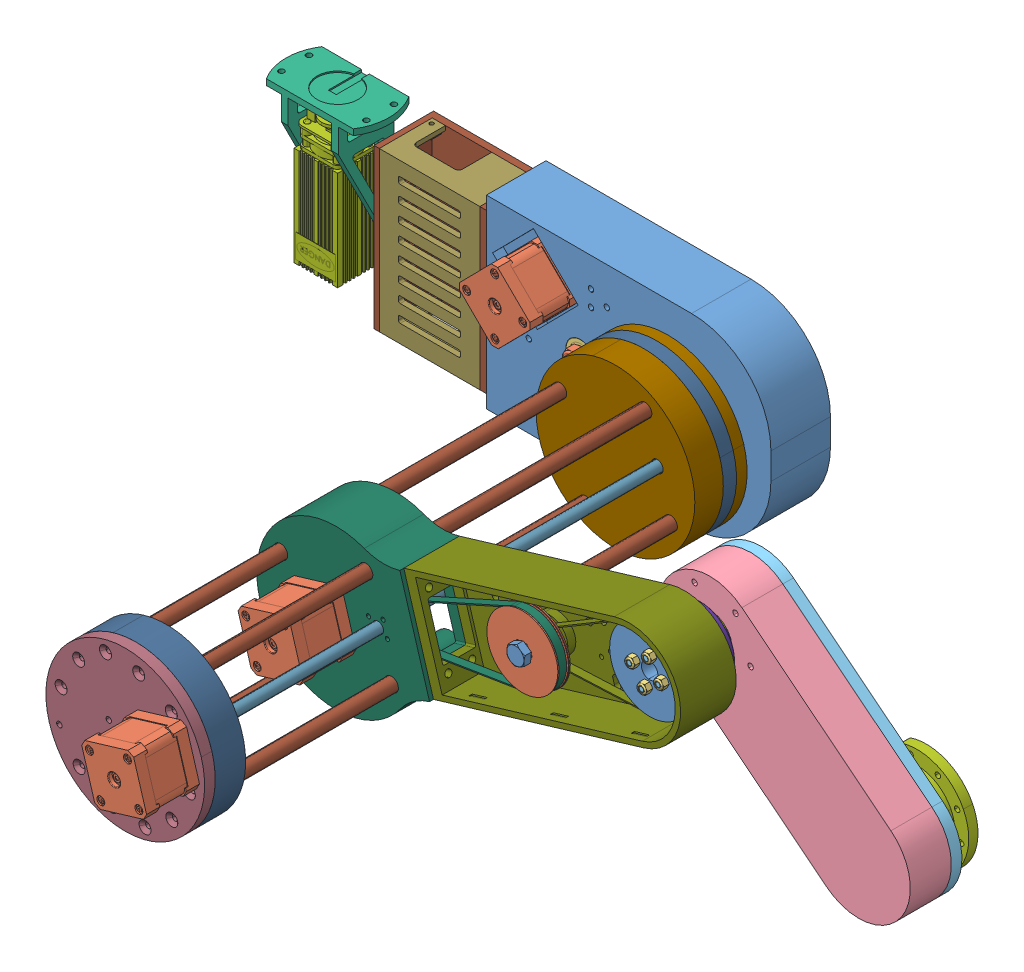
SolidWorks assembly SCARA Robot 3D Model dimensions, configuration Default. Lengths in mm.
Overall size (711.3 199.33 508).
113 component instances, 59 part files, 0 mates.
Components (placement in the parent):
- SCARA Robot 3D Model.STEP-1: SCARA Robot 3D Model.STEP [Default] at origin size (715.3 199.33 508)
  - Gripper Mechanism_Gripper Mechanism.STEP-1: Gripper Mechanism_Gripper Mechanism.STEP [Default] at (330.7722 20.5016 165.2282) x (0.989399 0.145223 0) z (0 0 -1) size (125 64.7 115.06) (hidden)
    - Servo Holder_Servo Holder.STEP-1: Servo Holder_Servo Holder.STEP [Default] at (30.6623 30.9064 53.3617) size (44 15 72.5)
    - Servo Motor MG996R 3D Model_Servo Motor MG996R 3D Model.STEP-1: Servo Motor MG996R 3D Model_Servo Motor MG996R 3D Model.STEP [Default] at (30.6623 -0.2936 62.3617) x (0 0 1) z (-1 0 0) size (55.8 45.2 20.5)
    - Servo MG996R Horn_Servo MG996R Horn.STEP-1: Servo MG996R Horn_Servo MG996R Horn.STEP [Default] at (30.6623 44.9064 52.1117) x (0.468503 0 0.883462) z (-0.883462 0 0.468503) size (32 2.5 12)
    - Gripper Cover_Gripper Cover.STEP-1: Gripper Cover_Gripper Cover.STEP [Default] at (30.6623 56.4064 52.1117) x (-1 0 0) z (0 0 1) size (44 10.5 70)
    - Gripper Hand Left_Gripper Hand Left.STEP-1: Gripper Hand Left_Gripper Hand Left.STEP [Default] at (0.1145 53.9064 27.1117) size (26 4 105)
    - Gripper rail 6mm_Gripper rail 6mm.STEP-1: Gripper rail 6mm_Gripper rail 6mm.STEP [Default] at (-31.8377 44.9064 75.1117) x (0 0.568693 0.82255) z (0 0.82255 -0.568693) size (6 125 6)
    - Gripper End_Gripper End.STEP-1: Gripper End_Gripper End.STEP [Default] at (-23.3855 44.9064 114.1117) x (0 0 1) z (0 1 0) size (27.12 30 25.12)
    - Gripper Hand Right_Gripper Hand Left.STEP-1: Gripper Hand Right_Gripper Hand Left.STEP [Default] at (61.21 53.9064 27.1117) size (26 4 105)
    - Gripper rail 6mm_Gripper rail 6mm.STEP-2: Gripper rail 6mm_Gripper rail 6mm.STEP [Default] at (93.1623 44.9064 29.1117) x (0 0.838695 -0.544602) z (0 0.544602 0.838695) size (6 125 6)
    - Gripper Mechanism Slider_Gripper Mechanism Slider.STEP-1: Gripper Mechanism Slider_Gripper Mechanism Slider.STEP [Default] at (-20.8855 44.9064 52.1117) x (0 1 0) z (0 0 -1) size (18 26 60)
    - Gripper Mechanism Slider_Gripper Mechanism Slider.STEP-2: Gripper Mechanism Slider_Gripper Mechanism Slider.STEP [Default] at (82.21 44.9064 52.1117) x (0 -1 0) z (0 0 -1) size (18 26 60)
    - Gripper Hand Left_Gripper Hand Left.STEP-2: Gripper Hand Left_Gripper Hand Left.STEP [Default] at (0.1145 31.9064 27.1117) size (26 4 105)
    - Gripper Hand Right_Gripper Hand Left.STEP-2: Gripper Hand Right_Gripper Hand Left.STEP [Default] at (61.21 31.9064 27.1117) size (26 4 105)
    - Gripper End_Gripper End.STEP-2: Gripper End_Gripper End.STEP [Default] at (84.71 44.9064 114.1117) x (0 0 -1) z (0 1 0) size (27.12 30 25.12)
    - Gripper link 1_Gripper link 1.STEP-1: Gripper link 1_Gripper link 1.STEP [Default] at (24.3375 47.4064 40.185) x (0.897148 0 -0.441731) z (0.441731 0 0.897148) size (34.2 3.5 7.2)
    - Gripper link 2_Gripper link 2.STEP-1: Gripper link 2_Gripper link 2.STEP [Default] at (0.1145 39.9064 52.1117) x (-0.897148 0 0.441731) z (-0.441731 0 -0.897148) size (34.2 5 7.2)
    - Gripper link 1_Gripper link 1.STEP-2: Gripper link 1_Gripper link 1.STEP [Default] at (61.21 47.4064 52.1117) x (0.897148 0 -0.441731) z (0.441731 0 0.897148) size (34.2 3.5 7.2)
    - Gripper link 2_Gripper link 2.STEP-2: Gripper link 2_Gripper link 2.STEP [Default] at (36.9871 44.9064 64.0385) x (-0.897148 0 0.441731) z (0.441731 0 0.897148) size (34.2 5 7.2)
    - Gripper to J3 connector_Gripper to J3 connector.STEP-1: Gripper to J3 connector_Gripper to J3 connector.STEP [Default] at (30.6623 44.9064 17.1117) x (0 -1 0) z (1 0 0) size (39 4.5 78)
  - Base_Base.STEP-1: Base_Base.STEP [Default] x (1 0 0) z (0 -1 0) size (215 45 140)
  - Stepper NEMA 17 -  20mm shaft_Stepper NEMA 17 -  20mm shaft.STEP-1: Stepper NEMA 17 -  20mm shaft_Stepper NEMA 17 -  20mm shaft.STEP [Default] at (-89.369 -0.1561 63.0261) x (-0.712104 0.702074 0) z (0 0 -1) size (41 41 60)
  - Ball Bearing 608 - 8x22x7mm_Ball Bearing 608 - 8x22x7mm.STEP-1: Ball Bearing 608 - 8x22x7mm_Ball Bearing 608 - 8x22x7mm.STEP [Default] at (-36.5 0 3) x (0.721176 0.692752 0) z (0.692752 -0.721176 0) size (22 7 22)
  - Ball Bearing 608 - 8x22x7mm_Ball Bearing 608 - 8x22x7mm.STEP-2: Ball Bearing 608 - 8x22x7mm_Ball Bearing 608 - 8x22x7mm.STEP [Default] at (-36.5 0 -7.5) x (0.799042 0.601276 0) z (0.601276 -0.799042 0) size (22 7 22)
  - Thrust Bearing - 40x60x13_Thrust Bearing - 40x60x13.STEP-1: Thrust Bearing - 40x60x13_Thrust Bearing - 40x60x13.STEP [Default] at (42.5 0 -13) x (0.837169 0.546944 0) z (0.546944 -0.837169 0) size (60 13 60)
  - Thrust Bearing - 40x60x13_Thrust Bearing - 40x60x13.STEP-2: Thrust Bearing - 40x60x13_Thrust Bearing - 40x60x13.STEP [Default] at (42.5 0 10) x (0.867502 0.497433 0) z (0.497433 -0.867502 0) size (60 13 60)
  - GT2 Pulley - 110 teeth - J1_GT2 Pulley - Parametric.STEP-1: GT2 Pulley - 110 teeth - J1_GT2 Pulley - Parametric.STEP [Default] at (42.5 0 -11.2) x (-0.957748 -0.287609 0) z (0.287609 -0.957748 0) size (71.92 22.4 71.92)
  - GT2 Pulley - 22 - 80 teeth_GT2 Pulley - Parametric.STEP-1: GT2 Pulley - 22 - 80 teeth_GT2 Pulley - Parametric.STEP [Default] at (-36.5 0 -26.7) x (0.869592 0.493772 0) z (0.493772 -0.869592 0) size (52.82 18.8 52.82)
  - GT2 Pulley - Parametric_GT2 Pulley - Parametric.STEP-1: GT2 Pulley - Parametric_GT2 Pulley - Parametric.STEP [Default] at (-69.2568 32.2954 -19.7) x (-1 0 0) z (0 -1 0) size (14.62 15.2 14.62)
  - M8 Washer_M8 Washer.STEP-1: M8 Washer_M8 Washer.STEP [Default] at (-36.5 0 -9.1) x (0.991676 -0.12876 0) z (-0.12876 -0.991676 0) size (14 1.6 14)
  - J1 coupler_J1 coupler.STEP-1: J1 coupler_J1 coupler.STEP [Default] at (42.5 0 23) x (0.287609 -0.957748 0) z (-0.957748 -0.287609 0) size (120 27 120)
  - Z-axis Bottom Plate_Z-axis Bottom Plate.STEP-1: Z-axis Bottom Plate_Z-axis Bottom Plate.STEP [Default] at (42.5 0 31) x (-0.287609 0.957748 0) z (0.957748 0.287609 0) size (120 10 120)
  - Smooth Rod D10mm L400mm_Smooth Rod D10mm L400mm.STEP-1: Smooth Rod D10mm L400mm_Smooth Rod D10mm L400mm.STEP [Default] at (65.0083 41.8285 25) x (-0.981883 -0.189487 0) z (-0.189487 0.981883 0) size (10 400 10)
  - Smooth Rod D10mm L400mm_Smooth Rod D10mm L400mm.STEP-2: Smooth Rod D10mm L400mm_Smooth Rod D10mm L400mm.STEP [Default] at (84.3285 -22.5083 25) x (0.837169 0.546944 0) z (0.546944 -0.837169 0) size (10 400 10)
  - Smooth Rod D10mm L400mm_Smooth Rod D10mm L400mm.STEP-3: Smooth Rod D10mm L400mm_Smooth Rod D10mm L400mm.STEP [Default] at (19.9917 -41.8285 25) x (0.837169 0.546944 0) z (0.546944 -0.837169 0) size (10 400 10)
  - Smooth Rod D10mm L400mm_Smooth Rod D10mm L400mm.STEP-4: Smooth Rod D10mm L400mm_Smooth Rod D10mm L400mm.STEP [Default] at (0.6715 22.5083 25) x (0.837169 0.546944 0) z (0.546944 -0.837169 0) size (10 400 10)
  - Smooth Rod Clamp_Smooth Rod Clamp.STEP-1: Smooth Rod Clamp_Smooth Rod Clamp.STEP [Default] at (84.3285 -22.5083 41) x (0.47386 0.8806 0) z (0.8806 -0.47386 0) size (39.1 14 26.4)
  - Smooth Rod Clamp_Smooth Rod Clamp.STEP-2: Smooth Rod Clamp_Smooth Rod Clamp.STEP [Default] at (19.9917 -41.8285 41) x (0.8806 -0.47386 0) z (-0.47386 -0.8806 0) size (39.1 14 26.4)
  - Smooth Rod Clamp_Smooth Rod Clamp.STEP-3: Smooth Rod Clamp_Smooth Rod Clamp.STEP [Default] at (0.6715 22.5083 41) x (-0.47386 -0.8806 0) z (-0.8806 0.47386 0) size (39.1 14 26.4)
  - Smooth Rod Clamp_Smooth Rod Clamp.STEP-4: Smooth Rod Clamp_Smooth Rod Clamp.STEP [Default] at (65.0083 41.8285 41) x (-0.8806 0.47386 0) z (0.47386 0.8806 0) size (39.1 14 26.4)
  - Z-axis Top Plate_Z-axis Top Plate.STEP-1: Z-axis Top Plate_Z-axis Top Plate.STEP [Default] at (42.5 0 425) x (-0.287609 0.957748 0) z (0.957748 0.287609 0) size (120 26 120)
  - Smooth Rod Clamp_Smooth Rod Clamp.STEP-5: Smooth Rod Clamp_Smooth Rod Clamp.STEP [Default] at (19.9917 -41.8285 411) x (0.8806 -0.47386 0) z (-0.47386 -0.8806 0) size (39.1 14 26.4)
  - Smooth Rod Clamp_Smooth Rod Clamp.STEP-6: Smooth Rod Clamp_Smooth Rod Clamp.STEP [Default] at (84.3285 -22.5083 411) x (0.47386 0.8806 0) z (0.8806 -0.47386 0) size (39.1 14 26.4)
  - Smooth Rod Clamp_Smooth Rod Clamp.STEP-7: Smooth Rod Clamp_Smooth Rod Clamp.STEP [Default] at (65.0083 41.8285 411) x (-0.8806 0.47386 0) z (0.47386 0.8806 0) size (39.1 14 26.4)
  - Smooth Rod Clamp_Smooth Rod Clamp.STEP-8: Smooth Rod Clamp_Smooth Rod Clamp.STEP [Default] at (0.6715 22.5083 411) x (-0.47386 -0.8806 0) z (-0.8806 0.47386 0) size (39.1 14 26.4)
  - Lead Screw D8mm L380mm_Lead Screw D8mm L380mm.STEP-1: Lead Screw D8mm L380mm_Lead Screw D8mm L380mm.STEP [Default] at (74.1057 9.4911 33) x (0.851295 0.524688 0) z (0.524688 -0.851295 0) size (8 380 8)
  - Ball Bearing 608 - 8x22x7mm_Ball Bearing 608 - 8x22x7mm.STEP-3: Ball Bearing 608 - 8x22x7mm_Ball Bearing 608 - 8x22x7mm.STEP [Default] at (74.1057 9.4911 34) x (0.619704 0.784836 0) z (0.784836 -0.619704 0) size (22 7 22)
  - Stepper NEMA 17 -  20mm shaft_Stepper NEMA 17 -  20mm shaft.STEP-2: Stepper NEMA 17 -  20mm shaft_Stepper NEMA 17 -  20mm shaft.STEP [Default] at (40.8832 -9.3202 494.0261) x (-0.287609 0.957748 0) z (0 0 -1) size (41 41 60)
  - Z-axis Mount Platform_Z-axis Mount Platform.STEP-1: Z-axis Mount Platform_Z-axis Mount Platform.STEP [Default] at (42.5 0 273.6165) x (0.287609 -0.957748 0) z (0.957748 0.287609 0) size (120 45 122)
  - Arm 1_Arm 1.STEP-1: Arm 1_Arm 1.STEP [Default] at (260.8665 65.5748 228.6165) x (0.957748 0.287609 0) z (0.287609 -0.957748 0) size (205 42 78)
  - Ball Bearing 608 - 8x22x7mm_Ball Bearing 608 - 8x22x7mm.STEP-4: Ball Bearing 608 - 8x22x7mm_Ball Bearing 608 - 8x22x7mm.STEP [Default] at (174.6692 39.69 244.6165) x (0.951346 -0.308126 0) z (0.308126 0.951346 0) size (22 7 22)
  - Ball Bearing 608 - 8x22x7mm_Ball Bearing 608 - 8x22x7mm.STEP-5: Ball Bearing 608 - 8x22x7mm_Ball Bearing 608 - 8x22x7mm.STEP [Default] at (174.6692 39.69 235.6165) x (0.947952 -0.318412 0) z (0.318412 0.947952 0) size (22 7 22)
  - J2 Coupler_J2 Coupler.STEP-1: J2 Coupler_J2 Coupler.STEP [Default] at (260.8665 65.5748 209.6165) x (0.148527 0.988908 0) z (0.988908 -0.148527 0) size (78 24 80.24) (hidden)
  - Thrust Bearing 35x52x12mm_Thrust Bearing 35x52x12mm.STEP-1: Thrust Bearing 35x52x12mm_Thrust Bearing 35x52x12mm.STEP [Default] at (260.8665 65.5748 216.6165) x (0.837351 0.546665 0) z (0.546665 -0.837351 0) size (52 12 52)
  - Ball Bearing 30x42x7mm_Ball Bearing 30x42x7mm.STEP-1: Ball Bearing 30x42x7mm_Ball Bearing 30x42x7mm.STEP [Default] at (260.8665 65.5748 231.6165) x (0.837351 0.546665 0) z (0.546665 -0.837351 0) size (42 7 42)
  - GT2 Pulley - 92 teeth - J2_GT2 Pulley - Parametric.STEP-1: GT2 Pulley - 92 teeth - J2_GT2 Pulley - Parametric.STEP [Default] at (260.8665 65.5748 246.8165) x (0.988908 -0.148527 0) z (-0.148527 -0.988908 0) size (60.46 20.4 60.46)
  - GT2 Pulley - 23 - 80 teeth_GT2 Pulley - Parametric.STEP-1: GT2 Pulley - 23 - 80 teeth_GT2 Pulley - Parametric.STEP [Default] at (174.6692 39.69 263.8165) x (-0.997581 -0.069512 0) z (0.069512 -0.997581 0) size (53.62 18.8 53.62)
  - Thrust Bearing 35x52x12mm_Thrust Bearing 35x52x12mm.STEP-2: Thrust Bearing 35x52x12mm_Thrust Bearing 35x52x12mm.STEP [Default] at (260.8665 65.5748 238.6165) x (0.837351 0.546665 0) z (0.546665 -0.837351 0) size (52 12 52)
  - Stepper NEMA 17 -  20mm shaft_Stepper NEMA 17 -  20mm shaft.STEP-3: Stepper NEMA 17 -  20mm shaft_Stepper NEMA 17 -  20mm shaft.STEP [Default] at (-0.3 -21.6874 334.6426) x (-0.287609 0.957748 0) z (0 0 -1) size (41 41 60)
  - GT2 Pulley - Parametric_GT2 Pulley - Parametric.STEP-2: GT2 Pulley - Parametric_GT2 Pulley - Parametric.STEP [Default] at (32.9225 -2.8761 263.8165) x (-0.907133 0.420845 0) z (-0.420845 -0.907133 0) size (14.62 15.2 14.62)
  - M8 Washer_M8 Washer.STEP-2: M8 Washer_M8 Washer.STEP [Default] at (174.6692 39.69 244.6165) x (0.991676 -0.12876 0) z (-0.12876 -0.991676 0) size (14 1.6 14)
  - Linear Bearing 10x19x29mm_Linear Bearing 10x19x29mm.STEP-1: Linear Bearing 10x19x29mm_Linear Bearing 10x19x29mm.STEP [Default] at (0.6715 22.5083 238.6165) x (0.787512 0.616299 0) z (0.616299 -0.787512 0) size (19 29 19)
  - Linear Bearing 10x19x29mm_Linear Bearing 10x19x29mm.STEP-2: Linear Bearing 10x19x29mm_Linear Bearing 10x19x29mm.STEP [Default] at (65.0083 41.8285 238.6165) x (0.973194 0.229988 0) z (0.229988 -0.973194 0) size (19 29 19)
  - Linear Bearing 10x19x29mm_Linear Bearing 10x19x29mm.STEP-3: Linear Bearing 10x19x29mm_Linear Bearing 10x19x29mm.STEP [Default] at (19.9917 -41.8285 238.6165) x (0.837169 0.546944 0) z (0.546944 -0.837169 0) size (19 29 19)
  - Linear Bearing 10x19x29mm_Linear Bearing 10x19x29mm.STEP-4: Linear Bearing 10x19x29mm_Linear Bearing 10x19x29mm.STEP [Default] at (84.3285 -22.5083 238.6165) x (0.837169 0.546944 0) z (0.546944 -0.837169 0) size (19 29 19)
  - Arm 2_Arm 2.STEP-1: Arm 2_Arm 2.STEP [Default] at (373.497 -24.149 209.6165) x (0.782156 -0.623082 0) z (0.623082 0.782156 0) size (222 31 78)
  - Arm 2 Cover_Arm 2 Cover.STEP-1: Arm 2 Cover_Arm 2 Cover.STEP [Default] at (373.497 -24.149 170.6165) x (0.782156 -0.623082 0) z (-0.623082 -0.782156 0) size (222 8 78)
  - Micro switch_Micro switch.STEP-1: Micro switch_Micro switch.STEP [Default] at (212.9946 41.2228 228.6165) x (0.710617 0.703579 0) z (0 0 -1) size (21.91 25.05 6)
  - NEMA 17 Stepper L24mm - 20mm shaft_NEMA 17 Stepper L24mm - 20mm shaft.STEP-1: NEMA 17 Stepper L24mm - 20mm shaft_NEMA 17 Stepper L24mm - 20mm shaft.STEP [Default] at (256.1736 69.3133 146.6165) x (0.782156 -0.623082 0) z (-0.623082 -0.782156 0) size (42 46 42) (hidden)
  - J3 Coupler_J3 Coupler.STEP-1: J3 Coupler_J3 Coupler.STEP [Default] at (367.6309 -19.4759 152.6165) x (-0.443856 0.896098 0) z (0.896098 0.443856 0) size (77.59 22 78)
  - Ball Bearing 30x42x7mm_Ball Bearing 30x42x7mm.STEP-2: Ball Bearing 30x42x7mm_Ball Bearing 30x42x7mm.STEP [Default] at (367.6309 -19.4759 178.6165) x (-1 -0.000333 0) z (0.000333 -1 0) size (42 7 42)
  - Thrust Bearing 35x52x12mm_Thrust Bearing 35x52x12mm.STEP-3: Thrust Bearing 35x52x12mm_Thrust Bearing 35x52x12mm.STEP [Default] at (367.6309 -19.4759 178.6165) x (0.492901 0.870085 0) z (0.870085 -0.492901 0) size (52 12 52)
  - Thrust Bearing 35x52x12mm_Thrust Bearing 35x52x12mm.STEP-4: Thrust Bearing 35x52x12mm_Thrust Bearing 35x52x12mm.STEP [Default] at (367.6309 -19.4759 170.6165) x (-0.90837 0.418168 0) z (-0.418168 -0.90837 0) size (52 12 52)
  - GT2 Pulley - 90 teeth - J3_GT2 Pulley - Parametric.STEP-1: GT2 Pulley - 90 teeth - J3_GT2 Pulley - Parametric.STEP [Default] at (367.6309 -19.4759 188.8165) x (-0.896098 -0.443856 0) z (-0.443856 0.896098 0) size (59.19 21.4 59.19) (hidden)
  - GT2 Pulley - Parametric_GT2 Pulley - Parametric.STEP-3: GT2 Pulley - Parametric_GT2 Pulley - Parametric.STEP [Default] at (256.1736 69.3133 188.8165) x (0.529245 0.848469 0) z (0.848469 -0.529245 0) size (14.62 15.2 14.62)
  - Micro switch_Micro switch.STEP-2: Micro switch_Micro switch.STEP [Default] at (-8.7411 -2.5547 16) x (0.882948 0.469472 0) z (0 0 -1) size (21.91 25.05 6)
  - Micro switch_Micro switch.STEP-3: Micro switch_Micro switch.STEP [Default] at (327.4651 0.3051 170.6165) x (0.983122 -0.182949 0) z (0 0 -1) size (21.91 25.05 6)
  - Lead Screw Nut 8mm_Lead Screw Nut 8mm.STEP-1: Lead Screw Nut 8mm_Lead Screw Nut 8mm.STEP [Default] at (74.1057 9.4911 264.1165) x (0.957748 0.287609 0) z (0.287609 -0.957748 0) size (22 15 22)
  - Arm 1 Cover_Arm 1 Cover.STEP-1: Arm 1 Cover_Arm 1 Cover.STEP [Default] at (260.8665 65.5748 273.6165) x (0.957748 0.287609 0) z (-0.287609 0.957748 0) size (205 11 78) (hidden)
  - Micro switch_Micro switch.STEP-4: Micro switch_Micro switch.STEP [Default] at (17.1693 -13.8714 412) x (0.957748 0.287609 0) z (-0.287609 0.957748 0) size (21.91 25.05 6)
  - Base cover_Base cover.STEP-1: Base cover_Base cover.STEP [Default] at (42.5 0 62.5) x (0.957748 0.287609 0) z (-0.287609 0.957748 0) size (120 21.5 120)
  - Top cover_Top cover.STEP-1: Top cover_Top cover.STEP [Default] at (42.5 0 402) x (0.957748 0.287609 0) z (0.287609 -0.957748 0) size (120 23 120)
  - Arduino Mega case_Arduino UNO case p1.STEP-1: Arduino Mega case_Arduino UNO case p1.STEP [Default] at (-150 60 -32.5) x (1 0 0) z (0 -1 0) size (85 45 120)
  - Arduino Mega case p2_Arduino UNO case p2.STEP-1: Arduino Mega case p2_Arduino UNO case p2.STEP [Default] at (-150.5 60 8) x (1 0 0) z (0 -1 0) size (76 40 120)
  - GT2 Belt 200mm_GT2 Belt 400mm.STEP-1: GT2 Belt 200mm_GT2 Belt 400mm.STEP [Default] at (-36.5 0 -25.7) x (0.712104 -0.702074 0) z (-0.702074 -0.712104 0) size (79.45 6 52.6)
  - GT2 Belt 300mm 2_GT2 Belt 400mm.STEP-1: GT2 Belt 300mm 2_GT2 Belt 400mm.STEP [Default] at (42.5 0 -17.2) x (1 0 0) z (0 -1 0) size (122.6 6 71.6)
  - GT2 Belt 400mm_GT2 Belt 400mm.STEP-1: GT2 Belt 400mm_GT2 Belt 400mm.STEP [Default] at (174.6692 39.69 257.8165) x (0.957748 0.287609 0) z (0.287609 -0.957748 0) size (181.45 6 52.6)
  - GT2 Belt 300mm_GT2 Belt 400mm.STEP-1: GT2 Belt 300mm_GT2 Belt 400mm.STEP [Default] at (260.8665 65.5748 247.8165) x (0.957748 0.287609 0) z (0.287609 -0.957748 0) size (128.2 6 60.2)
  - GT2 Belt 400mm 2_GT2 Belt 400mm.STEP-1: GT2 Belt 400mm 2_GT2 Belt 400mm.STEP [Default] at (367.6309 -19.4759 188.8165) x (0.782156 -0.623082 0) z (-0.623082 -0.782156 0) size (179.1 6 58.9)
  - Ball Bearing 35x47x7mm_Ball Bearing 30x42x7mm.STEP-1: Ball Bearing 35x47x7mm_Ball Bearing 30x42x7mm.STEP [Default] at (42.5 0 0) x (0.841539 0.540196 0) z (0.540196 -0.841539 0) size (47 7 47)
  - M8 45mm - Bolts_M8 45mm - Bolts.STEP-1: M8 45mm - Bolts_M8 45mm - Bolts.STEP [Default] at (-36.5 0 -8.05) x (0 0 1) z (-0.997493 -0.070764 0) size (50.3 15.01 13)
  - M8 Lock nut_M8 Lock nut.STEP-1: M8 Lock nut_M8 Lock nut.STEP [Default] at (-36.5 0 10) x (0.109161 -0.994024 0) z (-0.994024 -0.109161 0) size (13 8 15.01)
  - M8 45mm - Bolts_M8 45mm - Bolts.STEP-2: M8 45mm - Bolts_M8 45mm - Bolts.STEP [Default] at (174.6692 39.69 245.1665) x (0 0 -1) z (0.996158 -0.087573 0) size (50.3 15.01 13)
  - M8 Lock nut_M8 Lock nut.STEP-2: M8 Lock nut_M8 Lock nut.STEP [Default] at (174.6692 39.69 228.6165) x (-1 0 0) z (0 -1 0) size (13 8 15.01)
  - M4 Lock nut_M4 Lock nut.STEP-1: M4 Lock nut_M4 Lock nut.STEP [Default] at (249.9885 67.2086 255.0165) x (0.837169 0.546944 0) z (0.546944 -0.837169 0) size (7 5 8.08)
  - M4 Lock nut_M4 Lock nut.STEP-2: M4 Lock nut_M4 Lock nut.STEP [Default] at (262.5003 76.4528 255.0165) x (0.837169 0.546944 0) z (0.546944 -0.837169 0) size (7 5 8.08)
  - M4 Lock nut_M4 Lock nut.STEP-3: M4 Lock nut_M4 Lock nut.STEP [Default] at (271.7445 63.9411 255.0165) x (0.837169 0.546944 0) z (0.546944 -0.837169 0) size (7 5 8.08)
  - M4 Lock nut_M4 Lock nut.STEP-4: M4 Lock nut_M4 Lock nut.STEP [Default] at (259.2327 54.6969 255.0165) x (0.837169 0.546944 0) z (0.546944 -0.837169 0) size (7 5 8.08)
  - M4 60mm - Bolts_M4 60mm - Bolts.STEP-1: M4 60mm - Bolts_M4 60mm - Bolts.STEP [Default] at (38.9049 11.9718 28.8) x (-0.768027 0.640417 0) z (0 0 1) size (7.5 7.5 60)
  - M4 60mm - Bolts_M4 60mm - Bolts.STEP-2: M4 60mm - Bolts_M4 60mm - Bolts.STEP [Default] at (30.5282 -3.5951 28.8) x (0.837169 0.546944 0) z (0 0 1) size (7.5 7.5 60)
  - M4 60mm - Bolts_M4 60mm - Bolts.STEP-3: M4 60mm - Bolts_M4 60mm - Bolts.STEP [Default] at (54.4718 3.5951 28.8) x (0.837169 0.546944 0) z (0 0 1) size (7.5 7.5 60)
  - M4 60mm - Bolts_M4 60mm - Bolts.STEP-4: M4 60mm - Bolts_M4 60mm - Bolts.STEP [Default] at (46.0951 -11.9718 28.8) x (0.837169 0.546944 0) z (0 0 1) size (7.5 7.5 60)
  - M4 50mm - Bolts_M4 50mm - Bolts.STEP-1: M4 50mm - Bolts_M4 50mm - Bolts.STEP [Default] at (249.9885 67.2086 211.8165) x (0.837169 0.546944 0) z (0 0 -1) size (7.5 7.5 50)
  - M4 50mm - Bolts_M4 50mm - Bolts.STEP-2: M4 50mm - Bolts_M4 50mm - Bolts.STEP [Default] at (259.2327 54.6969 211.8165) x (0.837169 0.546944 0) z (0 0 -1) size (7.5 7.5 50)
  - M4 50mm - Bolts_M4 50mm - Bolts.STEP-3: M4 50mm - Bolts_M4 50mm - Bolts.STEP [Default] at (271.7445 63.9411 211.8165) x (0.837169 0.546944 0) z (0 0 -1) size (7.5 7.5 50)
  - M4 50mm - Bolts_M4 50mm - Bolts.STEP-4: M4 50mm - Bolts_M4 50mm - Bolts.STEP [Default] at (262.5003 76.4528 211.8165) x (0.837169 0.546944 0) z (0 0 -1) size (7.5 7.5 50)
  - M4 Lock nut_M4 Lock nut.STEP-5: M4 Lock nut_M4 Lock nut.STEP [Default] at (46.0951 -11.9718 -19.4) x (-1 0 0) z (0 -1 0) size (7 5 8.08)
  - M4 Lock nut_M4 Lock nut.STEP-6: M4 Lock nut_M4 Lock nut.STEP [Default] at (38.9049 11.9718 -19.4) x (-1 0 0) z (0 -1 0) size (7 5 8.08)
  - M4 Lock nut_M4 Lock nut.STEP-7: M4 Lock nut_M4 Lock nut.STEP [Default] at (54.4718 3.5951 -19.4) x (-1 0 0) z (0 -1 0) size (7 5 8.08)
  - M4 Lock nut_M4 Lock nut.STEP-8: M4 Lock nut_M4 Lock nut.STEP [Default] at (30.5282 -3.5951 -19.4) x (-1 0 0) z (0 -1 0) size (7 5 8.08)
  - Laser module holder_Gripper to J3 connector.STEP-1: Laser module holder_Gripper to J3 connector.STEP [Default] at (-244 55.5 -14) x (0 0 -1) z (1 0 0) size (42 114.5 78)
  - Laser Module 5.5W.STEP-1: Laser Module 5.5W.STEP [Default] at (-244 -62 -14) size (33 108.8 33.22)
